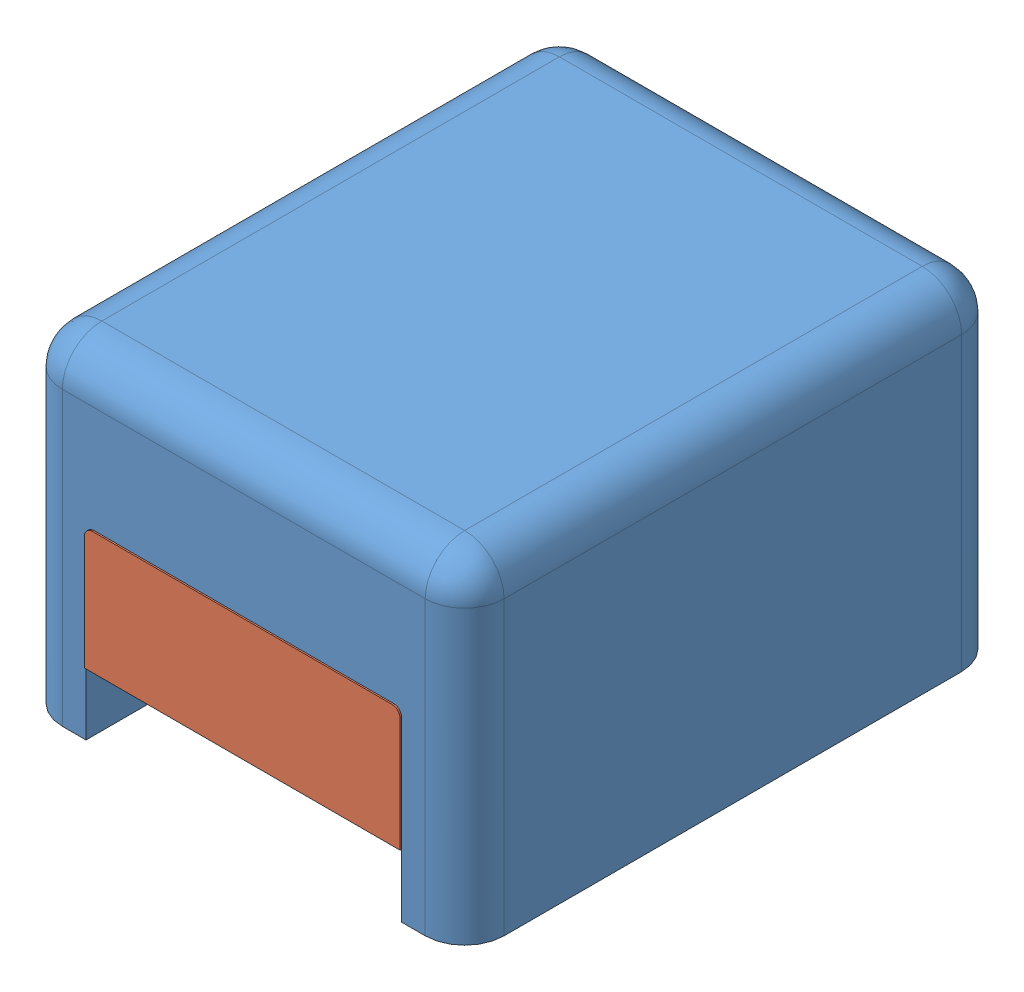
SolidWorks assembly Assembly, configuration Default. Lengths in mm.
Overall size (560 420 681.94).
2 component instances, 2 part files, 2 mates.
Components (placement in the parent):
- Oven Mainbody-1: Oven Mainbody [Default] at origin size (560 420 680)
- Door-1: Door [Default] at (80 80 1.9378) size (400 155 580)
Mates (geometry in assembly coordinates):
- Coincident3: coincident anti-aligned: plane of Oven Mainbody-1 through (562.4621 80 -580) normal (0 1 0); plane of Door-1 through (480 80 1.9378) normal (0 -1 0)
- Coincident4: coincident anti-aligned: plane of Oven Mainbody-1 through (480 0 -1204.9762) normal (-1 0 0); plane of Door-1 through (480 80 1.9378) normal (1 0 0)
